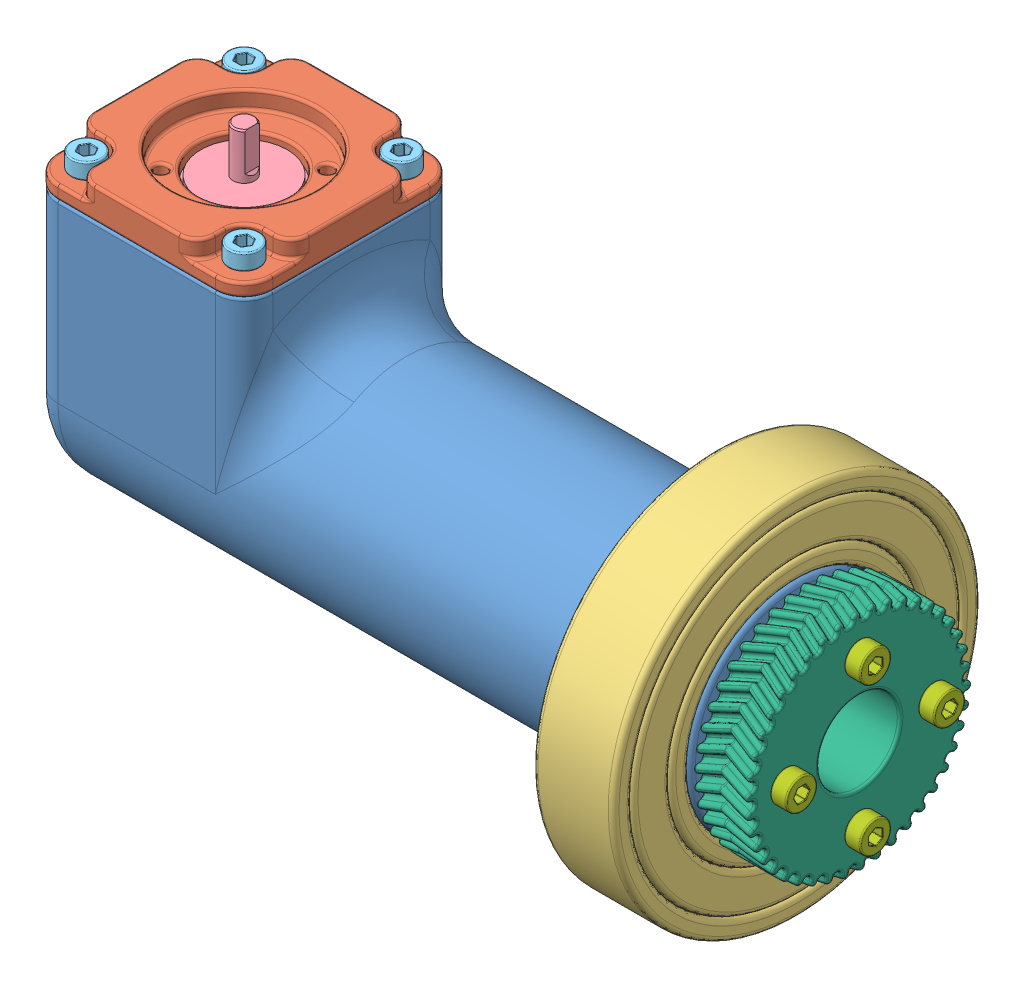
SolidWorks assembly Rotating_Arm_Assembly, configuration Default. Lengths in mm.
Overall size (137.03 81.76 78.52).
13 component instances, 7 part files, 21 mates.
Components (placement in the parent):
- Rotating_Prop_Arm-1: Rotating_Prop_Arm [Default] at (6.5662 50.6078 134.9373) x (0 -1 0) z (0 0 1) size (52.38 122.25 39.75)
- Prop_Top_Plate-2: Prop_Top_Plate [Default] at (-13.3088 85.6078 134.9373) size (40.31 5.75 40.31)
- Bearing-1: Bearing [Default] at (81.5662 50.6078 134.9373) x (0 0.169126 -0.985594) z (0 0.985594 0.169126) size (68 15 68)
- Nema_8-1: Nema_8 [Default] at (-13.3088 83.1078 134.9373) size (22 48 20)
- Prop_Plate_Bolt-5: Prop_Plate_Bolt [Default] at (-27.8713 88.6078 149.4998) x (-1 0 0) z (0 0 1) size (5.75 19.35 5.75)
- Prop_Plate_Bolt-6: Prop_Plate_Bolt [Default] at (-27.8713 88.6078 120.3748) x (-1 0 0) z (0 0 1) size (5.75 19.35 5.75)
- Prop_Plate_Bolt-7: Prop_Plate_Bolt [Default] at (1.2537 88.6078 120.3748) x (-1 0 0) z (0 0 1) size (5.75 19.35 5.75)
- Prop_Plate_Bolt-8: Prop_Plate_Bolt [Default] at (1.2537 88.6078 149.4998) x (-1 0 0) z (0 0 1) size (5.75 19.35 5.75)
- Arm_Gear-5: Arm_Gear [Default] at (95.5662 50.6078 134.9373) x (0 0 1) z (0 -1 0) size (41.65 11.51 41.66)
- Gear_Bolt-5: Gear_Bolt [Default] at (103.5662 64.2953 134.9373) x (0 1 0) z (0 0 1) size (5.75 23.37 5.75)
- Gear_Bolt-9: Gear_Bolt [Default] at (103.5662 50.6078 121.2498) x (0 0 -1) z (0 1 0) size (5.75 23.37 5.75)
- Gear_Bolt-10: Gear_Bolt [Default] at (103.5662 36.9203 134.9373) x (0 -1 0) z (0 0 -1) size (5.75 23.37 5.75)
- Gear_Bolt-11: Gear_Bolt [Default] at (103.5662 50.6078 148.6248) x (0 0 1) z (0 -1 0) size (5.75 23.37 5.75)
Mates (geometry in assembly coordinates):
- Width3: width: plane of Prop_Top_Plate-2 through (-33.1838 83.1078 154.8123) normal (0 0 1); plane of Prop_Top_Plate-2 through (-33.1838 83.1078 115.0623) normal (0 0 -1); plane of Rotating_Prop_Arm-1 through (-24.5588 3.788 146.1873) normal (0 0 -1); plane of Rotating_Prop_Arm-1 through (-24.5588 3.788 123.6873) normal (0 0 1)
- Width4: width: plane of Prop_Top_Plate-2 through (6.5662 83.1078 115.0623) normal (1 0 0); plane of Prop_Top_Plate-2 through (-33.1838 83.1078 115.0623) normal (-1 0 0); plane of Rotating_Prop_Arm-1 through (-24.5588 3.788 123.6873) normal (1 0 0); plane of Rotating_Prop_Arm-1 through (-2.0588 3.788 123.6873) normal (-1 0 0)
- Concentric1: concentric: cylinder of Rotating_Prop_Arm-1 through (89.0662 50.6078 134.9373) axis (-1 0 0) radius 19.875; cylinder of Bearing-1 through (89.0662 50.6078 134.9373) axis (-1 0 0) radius 20
- Coincident3: coincident: plane of Rotating_Prop_Arm-1 through (89.0662 50.6078 134.9373) normal (1 0 0); plane of Bearing-1 through (89.0662 50.6078 134.9373) normal (1 0 0)
- Coincident4: coincident: plane of Prop_Top_Plate-2 through (-13.3088 83.1078 134.9373) normal (0 -1 0); plane of Nema_8-1 through (-13.3088 83.1078 134.9373) normal (0 1 0)
- Concentric2: concentric: cylinder of Prop_Top_Plate-2 through (-13.3088 83.1078 134.9373) axis (0 1 0) radius 8.5; cylinder of Nema_8-1 through (-13.3088 84.6078 134.9373) axis (0 -1 0) radius 8
- Parallel1: parallel: plane of Nema_8-1 through (-3.3088 45.1078 144.9373) normal (0 0 1); plane of assembly through (0 0 0) normal (0 0 1)
- Coincident21: coincident: plane of Prop_Top_Plate-2 through (-13.3088 85.6078 134.9373) normal (0 1 0); plane of Prop_Plate_Bolt-5 through (-27.8713 85.6078 149.4998) normal (0 -1 0)
- Concentric10: concentric: cylinder of Prop_Top_Plate-2 through (-27.8713 83.1078 149.4998) axis (0 1 0) radius 1.6562; cylinder of Prop_Plate_Bolt-5 through (-27.8713 85.6078 149.4998) axis (0 1 0) radius 2.875
- Coincident22: coincident: plane of Prop_Top_Plate-2 through (-13.3088 85.6078 134.9373) normal (0 1 0); plane of Prop_Plate_Bolt-6 through (-27.8713 85.6078 120.3748) normal (0 -1 0)
- Concentric11: concentric: cylinder of Prop_Top_Plate-2 through (-27.8713 83.1078 120.3748) axis (0 1 0) radius 1.6562; cylinder of Prop_Plate_Bolt-6 through (-27.8713 85.6078 120.3748) axis (0 1 0) radius 2.875
- Coincident23: coincident: plane of Prop_Top_Plate-2 through (-13.3088 85.6078 134.9373) normal (0 1 0); plane of Prop_Plate_Bolt-7 through (1.2537 85.6078 120.3748) normal (0 -1 0)
- Concentric12: concentric: cylinder of Prop_Top_Plate-2 through (1.2537 83.1078 120.3748) axis (0 1 0) radius 1.6562; cylinder of Prop_Plate_Bolt-7 through (1.2537 85.6078 120.3748) axis (0 1 0) radius 2.875
- Coincident24: coincident: plane of Prop_Top_Plate-2 through (-13.3088 85.6078 134.9373) normal (0 1 0); plane of Prop_Plate_Bolt-8 through (1.2537 85.6078 149.4998) normal (0 -1 0)
- Concentric13: concentric: cylinder of Prop_Top_Plate-2 through (1.2537 83.1078 149.4998) axis (0 1 0) radius 1.6562; cylinder of Prop_Plate_Bolt-8 through (1.2537 85.6078 149.4998) axis (0 1 0) radius 2.875
- Coincident25: coincident: plane of Rotating_Prop_Arm-1 through (89.0662 50.6078 134.9373) normal (1 0 0); plane of Arm_Gear-5 through (89.0662 50.6078 134.9373) normal (-1 0 0)
- Concentric14: concentric: cylinder of Rotating_Prop_Arm-1 through (89.0662 50.6078 134.9373) axis (-1 0 0) radius 7.5; cylinder of Arm_Gear-5 through (100.5678 50.6078 134.9373) axis (-1 0 0) radius 7.5
- Parallel2: parallel: plane of Arm_Gear-5 through (95.5662 50.6078 134.9373) normal (0 0 1); plane of assembly through (0 0 0) normal (0 0 1)
- Coincident27: coincident: plane of Arm_Gear-5 through (100.5662 50.6078 134.9373) normal (1 0 0); plane of Gear_Bolt-5 through (100.5662 64.2953 134.9373) normal (-1 0 0)
- Concentric15: concentric: cylinder of Arm_Gear-5 through (100.5678 64.2953 134.9373) axis (-1 0 0) radius 1.625; cylinder of Gear_Bolt-5 through (100.5662 64.2953 134.9373) axis (1 0 0) radius 2.875
- Coincident28: coincident: plane of Rotating_Prop_Arm-1 through (-33.1838 83.1078 154.8123) normal (0 1 0); plane of Prop_Top_Plate-2 through (-13.3088 83.1078 134.9373) normal (0 -1 0)
